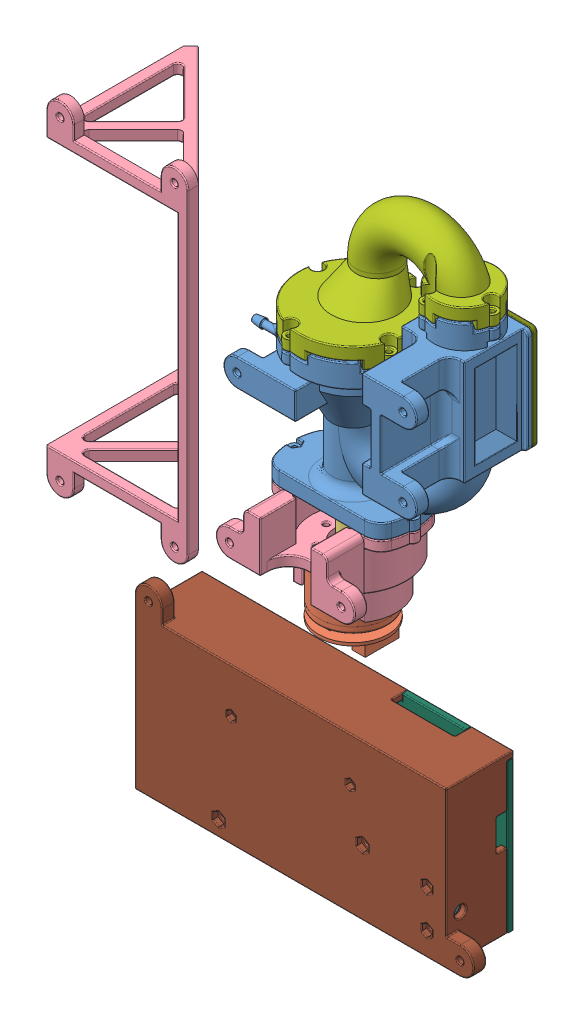
SolidWorks assembly FULL ASSEMBLY LAYOUT, configuration Default. Lengths in mm.
Overall size (235.43 266.85 134.74).
48 component instances, 34 part files, 43 mates.
Components (placement in the parent):
- Motor Connector Reference Assembly-1: Motor Connector Reference Assembly [Default] at origin size (95.4 152.33 58.74)
  - Water Tunnel-1: Water Tunnel [Default] at origin size (93.6 95.16 58.74)
  - 10kMotor-1: 10kMotor [Default] at (-41.4 -82.8 26.4) x (0 0 1) z (0 1 0) size (33 33 42.2)
  - Shaft Cupling 2 to 3-1: Shaft Cupling 2 to 3 [Default] at (-41.4 -70 26.4) x (0 0 1) z (0 1 0) size (12 12 20)
  - Motor Interface-1: Motor Interface [Default] at (0 -59 0) x (-1 0 0) z (0 -1 0) size (66 51.39 41.92)
  - 5000rpm10cmHead-1: 5000rpm10cmHead [Default] at (-41.4 2.484 26.4) x (0 0 -1) z (-1 0 0) size (33.19 12.79 25.21)
  - ImpellerShaft-1: ImpellerShaft [Default] at (-41.4 -70 26.4) x (0 0 1) z (0 1 0) size (3 3 74)
- U Tube-1: U Tube [Default] at (0 9.7382 0) x (1 0 0) z (0 1 0) size (83.46 52.58 53.84)
- Electrical Box Reference Assembly-1: Electrical Box Reference Assembly [Default] at (-38.9 -180.85 54.6912) x (-1 0 0) z (0 -1 0) size (161 32 88.7)
  - DC DC Converter 5V-1: DC DC Converter 5V [Default] at origin size (76.1 19 31.3)
  - Breadboard - Mini Modular (No adhesive)-1: Breadboard - Mini Modular (No adhesive) [Default] at (0 0 -33.65) x (0 0 -1) z (1 0 0) size (36.4 8.2 48.4)
  - Breadboard - Mini Modular (No adhesive)-2: Breadboard - Mini Modular (No adhesive) [Default] at (47 0 -33.65) x (0 0 -1) z (1 0 0) size (36.4 8.2 48.4)
  - Breadboard - Mini Modular (No adhesive)-3: Breadboard - Mini Modular (No adhesive) [Default] at (-47 0 -33.65) x (0 0 -1) z (1 0 0) size (36.4 8.2 48.4)
  - 21 55 Barrel Jack-1: 21 55 Barrel Jack [Default] at (53.5 12.5 19.15) x (-1 0 0) z (0 0 1) size (12.3 12.3 25.9)
  - Electrical Box-1: Electrical Box [Default] x (-1 0 0) z (0 -1 0) size (161 86.8 32)
  - Barrel Jack Nut-1: Barrel Jack Nut [Default] at (53.5 12.5 12.95) x (0.866025 0.5 0) z (0 0 1) size (15.93 13.8 2.2)
  - Barrel Jack Washer-1: Barrel Jack Washer [Default] at (53.5 12.5 15.15) size (14 14 1)
  - Cable Lock-2: Cable Lock [Default] at (-71 0 0) x (0 -1 0) z (1 0 0) size (5.75 28.3 8.5)
  - Electrical Box Lid-1: Electrical Box Lid [Default] at (0 25 0) x (1 0 0) z (0 1 0) size (148 73.8 10)
- Camera Mount Reference Assembly-1: Camera Mount Reference Assembly [Default] at origin size (267.17 129.73 171.67) (hidden)
  - Water Tunnel-1: Water Tunnel [Default] at origin size (93.6 95.16 58.74) (hidden)
  - Arducam IMX219AF-1: Arducam IMX219AF [Default] at (60.2 0 20.3) x (0 1 0) z (1 0 0) size (382.24 286.19 308.6)
  - Arducam IMX219AF-2: Arducam IMX219AF [Default] at (-5.3 0 -45.2) x (0 -1 0) z (0 0 -1) size (382.24 286.19 308.6)
  - 5mm White LED-1: 5mm White LED [Default] at (0 -19.4708 -46.6949) x (1 0 0) z (0 -0.978428 0.206589) size (5.4 26.8 5.4)
  - 5mm White LED-2: 5mm White LED [Default] at (0 19.4708 -46.6949) x (1 0 0) z (0 -0.978428 -0.206589) size (5.4 26.8 5.4)
  - 5mm White LED-3: 5mm White LED [Default] at (61.74 -19.5245 15) x (0 0 1) z (-0.22637 -0.974041 0) size (5.4 26.8 5.4)
  - 5mm White LED-4: 5mm White LED [Default] at (61.74 19.5245 15) x (0 0 1) z (0.22637 -0.974041 0) size (5.4 26.8 5.4)
  - Camera Mount-1: Camera Mount [Default] at (-5.3 0 -45.2) x (0 1 0) z (0 0 1) size (50.45 118.63 103.89)
  - Jetson Mount Reference Assembly-1: Jetson Mount Reference Assembly [Default] at (34.246 111.7133 -83.3741) x (0.707107 0 0.707107) z (0.707107 0 -0.707107) size (136.69 127.15 104.23) (hidden)
    - NanoBoxABSforB01_Bottom-1: NanoBoxABSforB01_Bottom [Default] at origin size (131.92 90.31 31)
    - Jetson Mount-1: Jetson Mount [Default] x (-1 0 0) z (0 0 -1) size (136.69 127.15 73.23)
    - NanoBoxABSforB01_Top-1: NanoBoxABSforB01_Top [Default] at (250 -0.2998 30.7) x (-1 0 0) z (0 0 -1) size (105.92 84.31 25)
- Lid-1: Lid [Default] at (0 0 0.1929) x (0 1 0) z (0 0 1) size (50 35 12.51)
- Lid Lock-1: Lid Lock [Default] at (-1 -92.5372 0.1929) x (1 0 0) z (0 1 0) size (45 12.5 82.5) (hidden)
- 5000rpm10cmHead-1: 5000rpm10cmHead [Default] at (-41.4 2.484 26.4) x (0.00734 0 0.999973) z (0.999973 0 -0.00734) size (33.19 12.79 25.21) (hidden)
- UtubeGasket-1: UtubeGasket [Default] at (0 32.1 15) x (0.300918 0 0.95365) z (0 1 0) size (16 16 1)
- MotorGasket-1: MotorGasket [Default] at (-41.4 9 26.4) x (0.999738 0 0.022879) z (-0.022879 0 0.999738) size (38.8 1 38.8)
- K_type_sensor-1: K_type_sensor [Default] at (-32.3599 -10 2.4303) x (-0.997941 -0.064145 0) z (0 0 1) size (4 4 40.6)
- OXROB3-1: OXROB3 [Default] at (-41.4 -31.75 -7.7059) x (0.893499 -0.449066 0) z (0 0 1) size (3.7 3.7 65)
- SealingRing-1: SealingRing [Default] at (-41.4 -46 26.4) x (0.536311 0 -0.84402) z (0 -1 0) size (10 10 6)
- Pump Rack Reference Assembly-2: Pump Rack Reference Assembly [Default] at (-137.1273 14.05 4.1639) x (-0.707107 0 -0.707107) z (-0.707107 0 0.707107) size (93.47 162.6 50.9)
  - Pump-1: Pump [Default] at origin size (54.7 55.8 65.4) (hidden)
  - Pump Rack-2: Pump Rack [Default] at origin size (93.47 162.6 50.9)
  - Pump-2: Pump [Default] at (0 60.8 0) size (54.7 55.8 65.4) (hidden)
- MainPlatform-1: MainPlatform [Default] at (-38.9 -180.85 58.6912) size (202.98 264.95 5) (hidden)
- jetsonPlatform-1: jetsonPlatform [Default] at (-5.3 0 58.6912) x (0 1 0) z (0 0 1) size (127.15 148.28 5) (hidden)
- Assembly Connector Plate-1: Assembly Connector Plate [Default] at (-5.3 0 52.6912) x (0 -1 0) z (0 0 -1) size (50 29.5 6) (hidden)
- bearing-1: bearing [Default] at (-41.4 -59 26.4) size (10 4 10)
Mates (geometry in assembly coordinates):
- Coincident1: coordinate: point of Motor Connector Reference Assembly-1/Water Tunnel-1
- Coincident5: coincident aligned: plane of Motor Connector Reference Assembly-1/Motor Interface-1 through (0 0 58.6912) normal (0 0 1); plane of Electrical Box Reference Assembly-1/Electrical Box-1 through (-38.9 -180.85 58.6912) normal (0 0 1)
- Coincident6: coincident: unknown of Motor Connector Reference Assembly-1/Water Tunnel-1; unknown of Camera Mount Reference Assembly-1/Water Tunnel-1
- Parallel2: parallel anti-aligned: plane of Motor Connector Reference Assembly-1/Water Tunnel-1 through (0 0 20) normal (0 0 -1); plane of Lid-1 through (-5 15 10.1929) normal (0 0 1)
- Concentric1: concentric anti-aligned: cylinder of Motor Connector Reference Assembly-1/Water Tunnel-1 through (15 22.5 2.5) axis (0 0 -1) radius 2.5; cylinder of Lid-1 through (15 22.5 -2.3071) axis (0 0 1) radius 2.5
- Concentric2: concentric anti-aligned: cylinder of Motor Connector Reference Assembly-1/Water Tunnel-1 through (-15 -22.5 2.5) axis (0 0 -1) radius 2.5; cylinder of Lid-1 through (-15 -22.5 -2.3071) axis (0 0 1) radius 2.5
- Concentric3: concentric anti-aligned: cylinder of Motor Connector Reference Assembly-1/Water Tunnel-1 through (-41.4 -4 26.4) axis (0 1 0) radius 16.4; cylinder of 5000rpm10cmHead-1 through (-41.4 13.2426 26.4) axis (0 -1 0) radius 1.5
- Coincident13: coincident aligned: plane of Motor Connector Reference Assembly-1/Water Tunnel-1 through (0 9 0) normal (0 1 0); plane of 5000rpm10cmHead-1 through (-41.4 9 26.4) normal (0 1 0)
- Coincident14: coincident anti-aligned: plane of Motor Connector Reference Assembly-1/Water Tunnel-1 through (0 9 0) normal (0 1 0); plane of MotorGasket-1 through (-41.4 9 26.4) normal (0 -1 0)
- Concentric4: concentric anti-aligned: cylinder of Motor Connector Reference Assembly-1/Water Tunnel-1 through (-41.4 -4 26.4) axis (0 1 0) radius 16.4; cylinder of MotorGasket-1 through (-41.4 10 26.4) axis (0 -1 0) radius 16.4
- Coincident15: coincident anti-aligned: plane of Motor Connector Reference Assembly-1/Water Tunnel-1 through (0 32.1 0) normal (0 1 0); plane of UtubeGasket-1 through (0 32.1 15) normal (0 -1 0)
- Concentric5: concentric aligned: cylinder of Motor Connector Reference Assembly-1/Water Tunnel-1 through (0 27.1 15) axis (0 -1 0) radius 14.5466; cylinder of UtubeGasket-1 through (0 33.1 15) axis (0 -1 0) radius 5
- Concentric6: concentric aligned: cylinder of Motor Connector Reference Assembly-1/Water Tunnel-1 through (-32.3599 -10 32.764) axis (0 0 -1) radius 2.25; cylinder of K_type_sensor-1 through (-32.3599 -10 33.0303) axis (0 0 -1) radius 2
- Concentric7: concentric aligned: cylinder of Motor Connector Reference Assembly-1/Water Tunnel-1 through (-41.4 -31.75 30.6426) axis (0 0 -1) radius 1.5; cylinder of OXROB3-1 through (-41.4 -31.75 22.2941) axis (0 0 -1) radius 1.5
- Concentric8: concentric aligned: cylinder of Motor Connector Reference Assembly-1/Water Tunnel-1 through (-41.4 -4 26.4) axis (0 1 0) radius 16.4; cylinder of SealingRing-1 through (-41.4 -52 26.4) axis (0 1 0) radius 5
- Coincident16: coincident anti-aligned: plane of Motor Connector Reference Assembly-1/Water Tunnel-1 through (-41.4 -52 26.4) normal (0 1 0); plane of SealingRing-1 through (-41.4 -52 26.4) normal (0 -1 0)
- Coincident17: coincident aligned: plane of Motor Connector Reference Assembly-1/Motor Interface-1 through (0 0 58.6912) normal (0 0 1); plane of Pump Rack Reference Assembly-1/Pump Rack-2 through (-88.7309 -106.1706 58.6912) normal (0 0 1)
- Parallel3: parallel anti-aligned: plane of Motor Connector Reference Assembly-1/Water Tunnel-1 through (-15 -25 30) normal (-1 0 0); plane of Pump Rack Reference Assembly-1/Pump Rack-2 through (-88.7309 -106.1706 53.6912) normal (1 0 0)
- Parallel4: parallel anti-aligned: plane of Motor Connector Reference Assembly-1/Motor Interface-1 through (-41.4 -82.8 26.4) normal (0 -1 0); plane of Electrical Box Reference Assembly-1/Electrical Box-1 through (-38.9 -126.2 56.1912) normal (0 1 0)
- Distance1: distance = 10 mm anti-aligned: plane of Electrical Box Reference Assembly-1/Electrical Box-1 through (-38.9 -126.2 56.1912) normal (0 1 0); plane of Motor Connector Reference Assembly-1/10kMotor-1 through (-41.4 -116.2 26.4) normal (0 -1 0)
- Distance2: distance = 10 mm aligned: plane of Electrical Box Reference Assembly-1/Electrical Box-1 through (-14.9 -113.2 29.6912) normal (1 0 0); cylinder of Motor Connector Reference Assembly-1/10kMotor-1 through (-41.4 -108.6 26.4) axis (0 -1 0) radius 16.5
- Coincident28: coincident aligned: plane of Motor Connector Reference Assembly-1/Water Tunnel-1 through (0 0 58.6912) normal (0 0 1); plane of Pump Rack Reference Assembly-2/Pump Rack-2 through (-87.6 -84.65 58.6912) normal (0 0 1)
- Coincident29: coincident aligned: plane of Motor Connector Reference Assembly-1/Water Tunnel-1 through (0 5.45 0) normal (0 1 0); plane of Pump Rack Reference Assembly-2 through (-137.1273 5.45 4.1639) normal (0 1 0)
- Distance6: distance = 15 mm anti-aligned: plane of Pump Rack Reference Assembly-2/Pump Rack-2 through (-87.6 -84.65 53.6912) normal (1 0 0); plane of Motor Connector Reference Assembly-1/Water Tunnel-1 through (-72.6 5.45 42.05) normal (-1 0 0)
- InPlace1: in place: plane of ? through (-38.9 -179.85 58.6912) normal (0 0 1); plane of ? through (0 0 58.6912) normal (0 0 1); moOrthogonalPlaneRef_w of ? through (-38.9 -179.85 58.6912) normal (0 0 1); plane of ? through (0 0 58.6912) normal (0 1 0); plane of ? through (-38.9 -179.85 58.6912) normal (0 0 1); plane of ? through (0 0 58.6912) normal (1 0 0); plane of Electrical Box Reference Assembly-1/Electrical Box-1 through (-38.9 -180.85 58.6912) normal (0 0 1); unknown of MainPlatform-1
- Coincident31: coincident aligned: plane of Electrical Box Reference Assembly-1/Electrical Box-1; plane of MainPlatform-1
- Coincident32: coincident aligned: moOrthogonalPlaneRef_w of Electrical Box Reference Assembly-1/Electrical Box-1 through (-38.9 -180.85 58.6912) normal (0 1 0); plane of MainPlatform-1 through (-38.9 -180.85 58.6912) normal (0 1 0)
- Coincident33: coincident anti-aligned: moOrthogonalPlaneRef_w of Electrical Box Reference Assembly-1/Electrical Box-1 through (-38.9 -180.85 58.6912) normal (-1 0 0); plane of MainPlatform-1 through (-38.9 -180.85 58.6912) normal (1 0 0)
- InPlace2: in place: plane of Camera Mount Reference Assembly-1/Camera Mount-1 through (60.2 92.0065 58.6912) normal (0 0 1); plane of ? through (0 0 58.6912) normal (0 0 1); plane of Camera Mount Reference Assembly-1/Camera Mount-1 through (60.2 92.0065 58.6912) normal (0 0 1); plane of ? through (0 0 58.6912) normal (0 1 0); plane of Camera Mount Reference Assembly-1/Camera Mount-1 through (60.2 92.0065 58.6912) normal (0 0 1); plane of ? through (0 0 58.6912) normal (1 0 0); plane of Camera Mount Reference Assembly-1/Camera Mount-1 through (60.2 92.0065 58.6912) normal (0 0 1); unknown of jetsonPlatform-1
- Coincident34: coincident aligned: plane of Camera Mount Reference Assembly-1/Camera Mount-1; plane of jetsonPlatform-1
- Coincident35: coincident aligned: moOrthogonalPlaneRef_w of Camera Mount Reference Assembly-1/Camera Mount-1 through (-5.3 0 58.6912) normal (-1 0 0); plane of jetsonPlatform-1 through (-5.3 0 58.6912) normal (-1 0 0)
- Coincident36: coincident anti-aligned: moOrthogonalPlaneRef_w of Camera Mount Reference Assembly-1/Camera Mount-1 through (-5.3 0 58.6912) normal (0 -1 0); plane of jetsonPlatform-1 through (-5.3 0 58.6912) normal (0 1 0)
- InPlace3: in place: plane of Camera Mount Reference Assembly-1/Camera Mount-1 through (55.2 92.0065 52.6912) normal (0 0 -1); plane of ? through (0 0 52.6912) normal (0 0 -1); plane of Camera Mount Reference Assembly-1/Camera Mount-1 through (55.2 92.0065 52.6912) normal (0 0 -1); plane of ? through (0 0 52.6912) normal (0 1 0); plane of Camera Mount Reference Assembly-1/Camera Mount-1 through (55.2 92.0065 52.6912) normal (0 0 -1); plane of ? through (0 0 52.6912) normal (-1 0 0); plane of Camera Mount Reference Assembly-1/Camera Mount-1 through (55.2 92.0065 52.6912) normal (0 0 -1); unknown of Assembly Connector Plate-1
- Coincident37: coincident aligned: plane of Camera Mount Reference Assembly-1/Camera Mount-1; plane of Assembly Connector Plate-1
- Coincident38: coincident aligned: moOrthogonalPlaneRef_w of Camera Mount Reference Assembly-1/Camera Mount-1 through (-5.3 0 52.6912) normal (-1 0 0); plane of Assembly Connector Plate-1 through (-5.3 0 52.6912) normal (-1 0 0)
- Coincident39: coincident anti-aligned: moOrthogonalPlaneRef_w of Camera Mount Reference Assembly-1/Camera Mount-1 through (-5.3 0 52.6912) normal (0 1 0); plane of Assembly Connector Plate-1 through (-5.3 0 52.6912) normal (0 -1 0)
- Parallel5: parallel anti-aligned: plane of Motor Connector Reference Assembly-1/Water Tunnel-1 through (-44.4772 13 5.4681) normal (0.992527 0 -0.122022); plane of U Tube-1 through (-43.9809 13.7382 5.407) normal (-0.992527 0 0.122022)
- Parallel6: parallel anti-aligned: plane of Motor Connector Reference Assembly-1/Water Tunnel-1 through (0.5 36.1 0) normal (-1 0 0); plane of U Tube-1 through (0 36.8382 0) normal (1 0 0)
- Concentric9: concentric anti-aligned: cylinder of Motor Connector Reference Assembly-1/Water Tunnel-1 through (-41.4 4 26.4) axis (0 1 0) radius 25.8513; cylinder of U Tube-1 through (-41.4 14.7382 26.4) axis (0 -1 0) radius 25.8513
- Distance7: distance = 0.5 mm anti-aligned: plane of Lid Lock-1 through (17 -42.5372 -2.8071) normal (-1 0 0); plane of Lid-1 through (17.5 22.5 -2.3071) normal (1 0 0)
- Distance8: distance = 0.5 mm anti-aligned: plane of Lid Lock-1 through (-19 -42.5372 -2.8071) normal (0 0 1); plane of Lid-1 through (-15 22.5 -2.3071) normal (0 0 -1)
- Concentric10: concentric anti-aligned: cylinder of Motor Connector Reference Assembly-1/Water Tunnel-1 through (-41.4 -59 26.4) axis (0 1 0) radius 5; cylinder of bearing-1 through (-41.4 -55 26.4) axis (0 -1 0) radius 5
- Coincident30: coincident aligned: plane of Motor Connector Reference Assembly-1/Water Tunnel-1 through (-41.4 -59 26.4) normal (0 -1 0); plane of bearing-1 through (-41.4 -59 26.4) normal (0 -1 0)
